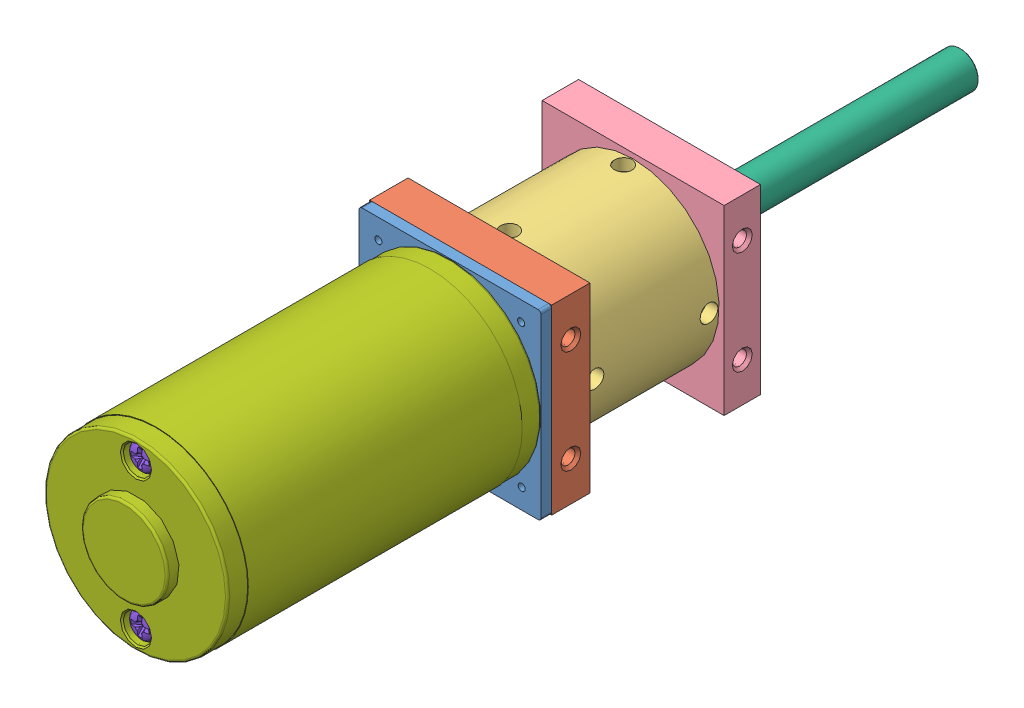
SolidWorks assembly BB2, configuration Default. Lengths in mm.
Overall size (64.41 64.41 215.73).
11 component instances, 8 part files, 0 mates.
Components (placement in the parent):
- BB2-InterfacePlate-1-1: BB2-InterfacePlate-1 [Default] at origin size (63.5 63.5 3.7)
- BB2-BackPlate-1-1: BB2-BackPlate-1 [Default] at (0 0 -8.55) x (0 -1 0) z (0 0 1) size (63.5 63.5 22.41)
- BB2-RingGear-1-1: BB2-RingGear-1 [Default] at (0 0 -15.25) x (1 0 0) z (0 0 -1) size (60 60 46.8)
- BB2-FrontPlate-1-1: BB2-FrontPlate-1 [Default] at (0 0 -68.4) x (0 1 0) z (0 0 -1) size (63.5 63.5 18.7)
- br-8-1-1: br-8-1 [Default] at (0 0 -70.7812) x (1 0 0) z (0 0 -1) size (28.57 28.57 7.94)
- br-8-1-2: br-8-1 [Default] at (0 0 -62.8438) x (0.905117 -0.425162 0) z (0 0 1) size (28.57 28.57 7.94)
- BB2-OutputShaft-1-1: BB2-OutputShaft-1 [Default] at (0 0 -112.85) x (0.213787 -0.97688 0) z (0 0 1) size (12.7 12.7 59)
- CIM Motor-1-1: CIM Motor-1 [Default] at (0 0 8.85) x (1 0 0) z (0 0 -1) size (64.41 64.41 149.34)
  - CIM motor-1-1: CIM motor-1 [Default] at origin size (64.41 64.41 149.34)
  - 10-24 UNC x 4_ Phillips Pan Head-1-1: 10-24 UNC x 4_ Phillips Pan Head-1 [Default] at (0 25.4 -98.0336) x (1 0 0) z (0 1 0) size (9.47 105.24 9.47)
  - 10-24 UNC x 4_ Phillips Pan Head-1-2: 10-24 UNC x 4_ Phillips Pan Head-1 [Default] at (0 -25.4 -98.0336) x (-1 0 0) z (0 -1 0) size (9.47 105.24 9.47)
